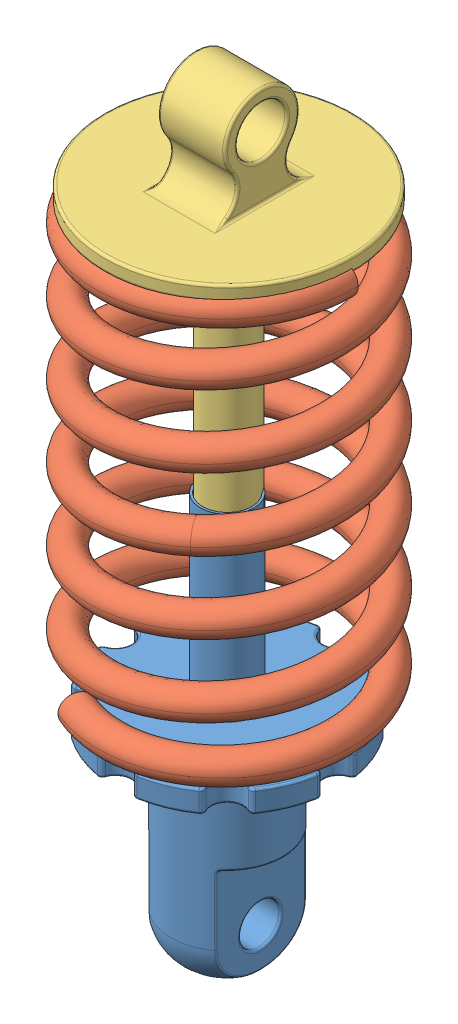
SolidWorks assembly Assem3-final-small, configuration Default. Lengths in mm.
Overall size (38.23 109.07 38.28).
3 component instances, 3 part files, 0 mates.
Components (placement in the parent):
- amortiguador_asm-part0-1: amortiguador_asm-part0 [Default] at (-2.7729 27.8012 43.5283) size (31.43 57.46 31.43)
- amortiguador_asm-part1-1: amortiguador_asm-part1 [Default] at (-3.3463 11.7715 42.6194) size (38.23 61.82 38.28)
- amortiguador_asm-part2-1: amortiguador_asm-part2 [Default] at (-3.3808 0.2745 42.701) size (35.47 56.75 35.47)
